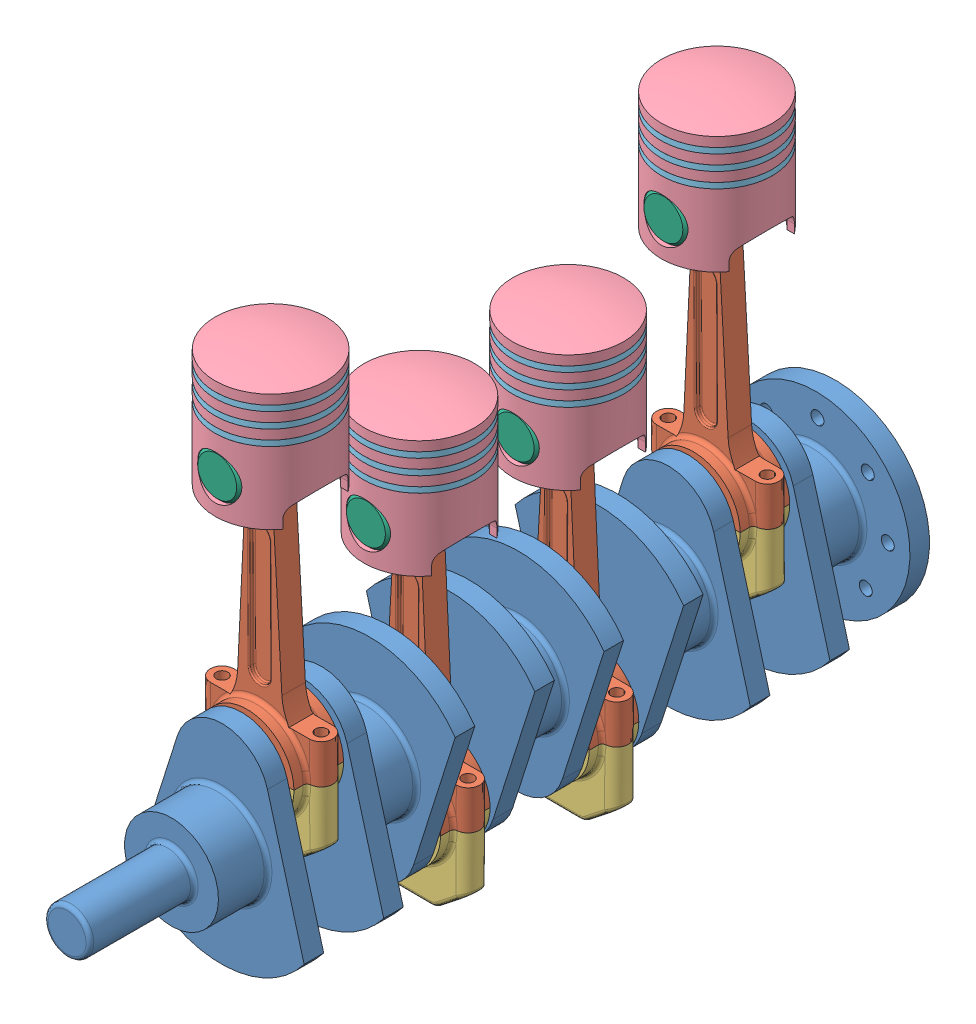
SolidWorks assembly Engine-2003092, configuration Default. Lengths in mm.
Overall size (147.06 418.41 589).
29 component instances, 6 part files, 66 mates.
Components (placement in the parent):
- Crankshaft-1: Crankshaft [Default] at (0 0 456) x (-0.999814 0.019293 0) z (0 0 1) size (144 160 589)
- Connecting rod-1: Connecting rod [Default] at (0 245.19 433) x (0.999991 0.004219 0) z (0 0 1) size (94 223.7 38)
- Connecting rod cap-1: Connecting rod cap [Default] at (0.8489 43.9918 433) x (-0.999991 -0.004219 0) z (0 0 1) size (94 60 38)
- Piston-1: Piston [Default] at (0 219.2199 433) size (85 95 85)
- Piston ring-1: Piston ring [Default] at (0 297.6199 433) size (85 4.3 85)
- Piston Pin-1: Piston Pin [Default] at (0 245.19 433) size (33.8 33.8 82)
- Piston ring-2: Piston ring [Default] at (0 286.0199 433) x (0.546944 0 -0.837169) z (0.837169 0 0.546944) size (85 4.3 85)
- Piston ring-4: Piston ring [Default] at (0 274.4199 433) x (0.546944 0 -0.837169) z (0.837169 0 0.546944) size (85 4.3 85)
- Piston-2: Piston [Default] at (0 131.2362 319) size (85 95 85)
- Piston ring-6: Piston ring [Default] at (0 209.6362 319) x (0.941458 0 -0.337131) z (0.337131 0 0.941458) size (85 4.3 85)
- Piston ring-7: Piston ring [Default] at (0 198.0362 319) x (0.23269 0 -0.972551) z (0.972551 0 0.23269) size (85 4.3 85)
- Piston ring-8: Piston ring [Default] at (0 186.4362 319) x (0.23269 0 -0.972551) z (0.972551 0 0.23269) size (85 4.3 85)
- Piston Pin-2: Piston Pin [Default] at (0 157.2064 319) x (0.216826 -0.97621 0) z (0 0 1) size (33.8 33.8 82)
- Connecting rod-2: Connecting rod [Default] at (0 157.2064 319) x (0.999991 -0.004219 0) z (0 0 1) size (94 223.7 38)
- Connecting rod cap-2: Connecting rod cap [Default] at (-0.8489 -43.9918 319) x (-0.999991 0.004219 0) z (0 0 1) size (94 60 38)
- Piston-4: Piston [Default] at (0 131.2362 205) x (-1 0 0) z (0 0 -1) size (85 95 85)
- Piston ring-12: Piston ring [Default] at (0 209.6362 205) x (0.790546 0 -0.612403) z (0.612403 0 0.790546) size (85 4.3 85)
- Piston ring-13: Piston ring [Default] at (0 198.0362 205) x (-0.0803 0 -0.996771) z (0.996771 0 -0.0803) size (85 4.3 85)
- Piston ring-14: Piston ring [Default] at (0 186.4362 205) x (-0.0803 0 -0.996771) z (0.996771 0 -0.0803) size (85 4.3 85)
- Piston Pin-4: Piston Pin [Default] at (0 157.2064 205) x (-0.34202 0.939693 0) z (0 0 -1) size (33.8 33.8 82)
- Connecting rod-4: Connecting rod [Default] at (0 157.2064 205) x (-0.999991 0.004219 0) z (0 0 -1) size (94 223.7 38)
- Connecting rod cap-4: Connecting rod cap [Default] at (-0.8489 -43.9918 205) x (0.999991 -0.004219 0) z (0 0 -1) size (94 60 38)
- Piston-6: Piston [Default] at (0 219.2199 91) x (-1 0 0) z (0 0 -1) size (85 95 85)
- Piston ring-18: Piston ring [Default] at (0 297.6199 91) x (0.6 0 -0.8) z (0.8 0 0.6) size (85 4.3 85)
- Piston ring-19: Piston ring [Default] at (0 286.0199 91) x (-0.341569 0 -0.939857) z (0.939857 0 -0.341569) size (85 4.3 85)
- Piston ring-20: Piston ring [Default] at (0 274.4199 91) x (-0.341569 0 -0.939857) z (0.939857 0 -0.341569) size (85 4.3 85)
- Piston Pin-6: Piston Pin [Default] at (0 245.19 91) x (-0.5 0.866025 0) z (0 0 -1) size (33.8 33.8 82)
- Connecting rod-6: Connecting rod [Default] at (0 245.19 91) x (-0.999991 -0.004219 0) z (0 0 -1) size (94 223.7 38)
- Connecting rod cap-6: Connecting rod cap [Default] at (0.8489 43.9918 91) x (0.999991 0.004219 0) z (0 0 -1) size (94 60 38)
Mates (geometry in assembly coordinates):
- Concentric1: concentric anti-aligned: cylinder of Crankshaft-1 through (0 0 589) axis (0 0 -1) radius 17.5
- Coincident1: coincident: plane of Crankshaft-1 through (0 0 589) normal (0 0 1)
- Coincident2: coincident aligned: plane of Piston-1 through (0 219.2199 433) normal (0 0 1); plane of Piston Pin-1 through (0 245.19 433) normal (0 0 1)
- Concentric2: concentric anti-aligned: cylinder of Piston-1 through (0 245.19 390.5) axis (0 0 1) radius 16.9; cylinder of Piston Pin-1 through (0 245.19 474) axis (0 0 -1) radius 16.9
- Concentric3: concentric aligned: cylinder of Piston-1 through (0 309.2199 433) axis (0 -1 0) radius 42.5; cylinder of Piston ring-1 through (0 301.9199 433) axis (0 -1 0) radius 42.5
- Coincident3: coincident anti-aligned: plane of Piston-1 through (0 297.6199 433) normal (0 1 0); plane of Piston ring-1 through (0 297.6199 433) normal (0 -1 0)
- Concentric4: concentric anti-aligned: cylinder of Piston-1 through (0 286.0199 433) axis (0 1 0) radius 39.5; cylinder of Piston ring-2 through (0 290.3199 433) axis (0 -1 0) radius 42.5
- Coincident4: coincident anti-aligned: plane of Piston-1 through (0 286.0199 433) normal (0 1 0); plane of Piston ring-2 through (0 286.0199 433) normal (0 -1 0)
- Concentric5: concentric anti-aligned: cylinder of Piston-1 through (0 274.4199 433) axis (0 1 0) radius 39.5; cylinder of Piston ring-4 through (0 278.7199 433) axis (0 -1 0) radius 42.5
- Coincident5: coincident anti-aligned: plane of Piston-1 through (0 274.4199 433) normal (0 1 0); plane of Piston ring-4 through (0 274.4199 433) normal (0 -1 0)
- Coincident6: coincident aligned: plane of Connecting rod-1 through (0 245.19 433) normal (0 0 1); plane of Piston-1 through (0 219.2199 433) normal (0 0 1)
- Concentric6: concentric aligned: cylinder of Connecting rod-1 through (0 245.19 452) axis (0 0 -1) radius 16.9; cylinder of Piston Pin-1 through (0 245.19 474) axis (0 0 -1) radius 16.9
- Concentric7: concentric aligned: cylinder of Connecting rod-1 through (38.8486 44.1521 433) axis (-0.004219 0.999991 0) radius 4.5; cylinder of Connecting rod cap-1 through (39.1017 -15.8473 433) axis (-0.004219 0.999991 0) radius 4.5
- Concentric8: concentric aligned: cylinder of Connecting rod-1 through (-37.1508 43.8315 433) axis (-0.004219 0.999991 0) radius 4.5; cylinder of Connecting rod cap-1 through (-36.8976 -16.168 433) axis (-0.004219 0.999991 0) radius 4.5
- Coincident7: coincident anti-aligned: plane of Connecting rod-1 through (0.8489 43.9918 452) normal (0.004219 -0.999991 0); plane of Connecting rod cap-1 through (36.8486 44.1437 452) normal (-0.004219 0.999991 0)
- Width1: width anti-aligned: plane of Crankshaft-1 through (0 0 410) normal (0 0 1); plane of Connecting rod-1 through (0 0 456) normal (0 0 -1); plane of Crankshaft-1 through (0 245.19 424) normal (0 0 -1); plane of Connecting rod-1 through (0 245.19 442) normal (0 0 1)
- Concentric9: concentric anti-aligned: cylinder of Crankshaft-1 through (0.8489 43.9918 410) axis (0 0 1) radius 27; cylinder of Connecting rod-1 through (0.8489 43.9918 452) axis (0 0 -1) radius 27
- Concentric10: concentric anti-aligned: cylinder of Piston-1 through (0 309.2199 433) axis (0 -1 0) radius 42.5
- Coincident9: coincident aligned: plane of Piston-2 through (0 131.2362 319) normal (0 0 1); plane of Piston Pin-2 through (0 157.2064 319) normal (0 0 1)
- Concentric11: concentric anti-aligned: cylinder of Piston-2 through (0 157.2064 276.5) axis (0 0 1) radius 16.9; cylinder of Piston Pin-2 through (0 157.2064 360) axis (0 0 -1) radius 16.9
- Concentric12: concentric aligned: cylinder of Piston-2 through (0 221.2362 319) axis (0 -1 0) radius 42.5; cylinder of Piston ring-6 through (0 213.9362 319) axis (0 -1 0) radius 42.5
- Coincident10: coincident anti-aligned: plane of Piston-2 through (0 209.6362 319) normal (0 1 0); plane of Piston ring-6 through (0 209.6362 319) normal (0 -1 0)
- Concentric13: concentric anti-aligned: cylinder of Piston-2 through (0 198.0362 319) axis (0 1 0) radius 39.5; cylinder of Piston ring-7 through (0 202.3362 319) axis (0 -1 0) radius 42.5
- Coincident11: coincident anti-aligned: plane of Piston-2 through (0 198.0362 319) normal (0 1 0); plane of Piston ring-7 through (0 198.0362 319) normal (0 -1 0)
- Concentric14: concentric anti-aligned: cylinder of Piston-2 through (0 186.4362 319) axis (0 1 0) radius 39.5; cylinder of Piston ring-8 through (0 190.7362 319) axis (0 -1 0) radius 42.5
- Coincident12: coincident anti-aligned: plane of Piston-2 through (0 186.4362 319) normal (0 1 0); plane of Piston ring-8 through (0 186.4362 319) normal (0 -1 0)
- Coincident13: coincident aligned: plane of Piston-2 through (0 131.2362 319) normal (0 0 1); plane of Connecting rod-2 through (0 157.2064 319) normal (0 0 1)
- Concentric15: concentric aligned: cylinder of Piston Pin-2 through (0 157.2064 360) axis (0 0 -1) radius 16.9; cylinder of Connecting rod-2 through (0 157.2064 338) axis (0 0 -1) radius 16.9
- Concentric16: concentric aligned: cylinder of Connecting rod-2 through (37.1508 -44.1521 319) axis (0.004219 0.999991 0) radius 4.5; cylinder of Connecting rod cap-2 through (36.8976 -104.1516 319) axis (0.004219 0.999991 0) radius 4.5
- Concentric17: concentric aligned: cylinder of Connecting rod-2 through (-38.8486 -43.8315 319) axis (0.004219 0.999991 0) radius 4.5; cylinder of Connecting rod cap-2 through (-39.1017 -103.8309 319) axis (0.004219 0.999991 0) radius 4.5
- Coincident14: coincident anti-aligned: plane of Connecting rod-2 through (-0.8489 -43.9918 338) normal (-0.004219 -0.999991 0); plane of Connecting rod cap-2 through (35.1508 -44.1437 338) normal (0.004219 0.999991 0)
- Width2: width anti-aligned: plane of Crankshaft-1 through (0 0 342) normal (0 0 -1); plane of Connecting rod-2 through (0 0 296) normal (0 0 1); plane of Crankshaft-1 through (0 157.2064 310) normal (0 0 -1); plane of Connecting rod-2 through (0 157.2064 328) normal (0 0 1)
- Concentric18: concentric anti-aligned: cylinder of Crankshaft-1 through (-0.8489 -43.9918 296) axis (0 0 1) radius 27; cylinder of Connecting rod-2 through (-0.8489 -43.9918 338) axis (0 0 -1) radius 27
- Concentric19: concentric anti-aligned: cylinder of Piston-2 through (0 221.2362 319) axis (0 -1 0) radius 42.5
- Coincident21: coincident aligned: plane of Piston-4 through (0 131.2362 205) normal (0 0 -1); plane of Piston Pin-4 through (0 157.2064 205) normal (0 0 -1)
- Concentric27: concentric anti-aligned: cylinder of Piston-4 through (0 157.2064 247.5) axis (0 0 -1) radius 16.9; cylinder of Piston Pin-4 through (0 157.2064 164) axis (0 0 1) radius 16.9
- Concentric28: concentric aligned: cylinder of Piston-4 through (0 221.2362 205) axis (0 -1 0) radius 42.5; cylinder of Piston ring-12 through (0 213.9362 205) axis (0 -1 0) radius 42.5
- Coincident22: coincident anti-aligned: plane of Piston-4 through (0 209.6362 205) normal (0 1 0); plane of Piston ring-12 through (0 209.6362 205) normal (0 -1 0)
- Concentric29: concentric anti-aligned: cylinder of Piston-4 through (0 198.0362 205) axis (0 1 0) radius 39.5; cylinder of Piston ring-13 through (0 202.3362 205) axis (0 -1 0) radius 42.5
- Coincident23: coincident anti-aligned: plane of Piston-4 through (0 198.0362 205) normal (0 1 0); plane of Piston ring-13 through (0 198.0362 205) normal (0 -1 0)
- Concentric30: concentric anti-aligned: cylinder of Piston-4 through (0 186.4362 205) axis (0 1 0) radius 39.5; cylinder of Piston ring-14 through (0 190.7362 205) axis (0 -1 0) radius 42.5
- Coincident24: coincident anti-aligned: plane of Piston-4 through (0 186.4362 205) normal (0 1 0); plane of Piston ring-14 through (0 186.4362 205) normal (0 -1 0)
- Coincident25: coincident aligned: plane of Piston-4 through (0 131.2362 205) normal (0 0 -1); plane of Connecting rod-4 through (0 157.2064 205) normal (0 0 -1)
- Concentric31: concentric aligned: cylinder of Piston Pin-4 through (0 157.2064 164) axis (0 0 1) radius 16.9; cylinder of Connecting rod-4 through (0 157.2064 186) axis (0 0 1) radius 16.9
- Concentric32: concentric aligned: cylinder of Connecting rod-4 through (-38.8486 -43.8315 205) axis (0.004219 0.999991 0) radius 4.5; cylinder of Connecting rod cap-4 through (-39.1017 -103.8309 205) axis (0.004219 0.999991 0) radius 4.5
- Concentric33: concentric aligned: cylinder of Connecting rod-4 through (37.1508 -44.1521 205) axis (0.004219 0.999991 0) radius 4.5; cylinder of Connecting rod cap-4 through (36.8976 -104.1516 205) axis (0.004219 0.999991 0) radius 4.5
- Coincident26: coincident anti-aligned: plane of Connecting rod-4 through (-0.8489 -43.9918 186) normal (-0.004219 -0.999991 0); plane of Connecting rod cap-4 through (-36.8486 -43.8399 186) normal (0.004219 0.999991 0)
- Width3: width anti-aligned: plane of Crankshaft-1 through (0 0 228) normal (0 0 -1); plane of Connecting rod-4 through (0 0 182) normal (0 0 1); plane of Crankshaft-1 through (0 157.2064 214) normal (0 0 1); plane of Connecting rod-4 through (0 157.2064 196) normal (0 0 -1)
- Concentric34: concentric anti-aligned: cylinder of Crankshaft-1 through (-0.8489 -43.9918 228) axis (0 0 -1) radius 27; cylinder of Connecting rod-4 through (-0.8489 -43.9918 186) axis (0 0 1) radius 27
- Concentric35: concentric anti-aligned: cylinder of Piston-4 through (0 221.2362 205) axis (0 -1 0) radius 42.5
- Coincident33: coincident aligned: plane of Piston-6 through (0 219.2199 91) normal (0 0 -1); plane of Piston Pin-6 through (0 245.19 91) normal (0 0 -1)
- Concentric43: concentric anti-aligned: cylinder of Piston-6 through (0 245.19 133.5) axis (0 0 -1) radius 16.9; cylinder of Piston Pin-6 through (0 245.19 50) axis (0 0 1) radius 16.9
- Concentric44: concentric aligned: cylinder of Piston-6 through (0 309.2199 91) axis (0 -1 0) radius 42.5; cylinder of Piston ring-18 through (0 301.9199 91) axis (0 -1 0) radius 42.5
- Coincident34: coincident anti-aligned: plane of Piston-6 through (0 297.6199 91) normal (0 1 0); plane of Piston ring-18 through (0 297.6199 91) normal (0 -1 0)
- Concentric45: concentric anti-aligned: cylinder of Piston-6 through (0 286.0199 91) axis (0 1 0) radius 39.5; cylinder of Piston ring-19 through (0 290.3199 91) axis (0 -1 0) radius 42.5
- Coincident35: coincident anti-aligned: plane of Piston-6 through (0 286.0199 91) normal (0 1 0); plane of Piston ring-19 through (0 286.0199 91) normal (0 -1 0)
- Concentric46: concentric anti-aligned: cylinder of Piston-6 through (0 274.4199 91) axis (0 1 0) radius 39.5; cylinder of Piston ring-20 through (0 278.7199 91) axis (0 -1 0) radius 42.5
- Coincident36: coincident anti-aligned: plane of Piston-6 through (0 274.4199 91) normal (0 1 0); plane of Piston ring-20 through (0 274.4199 91) normal (0 -1 0)
- Coincident37: coincident aligned: plane of Piston-6 through (0 219.2199 91) normal (0 0 -1); plane of Connecting rod-6 through (0 245.19 91) normal (0 0 -1)
- Concentric47: concentric aligned: cylinder of Piston Pin-6 through (0 245.19 50) axis (0 0 1) radius 16.9; cylinder of Connecting rod-6 through (0 245.19 72) axis (0 0 1) radius 16.9
- Concentric48: concentric aligned: cylinder of Connecting rod-6 through (-37.1508 43.8315 91) axis (-0.004219 0.999991 0) radius 4.5; cylinder of Connecting rod cap-6 through (-36.8976 -16.168 91) axis (-0.004219 0.999991 0) radius 4.5
- Concentric49: concentric aligned: cylinder of Connecting rod-6 through (38.8486 44.1521 91) axis (-0.004219 0.999991 0) radius 4.5; cylinder of Connecting rod cap-6 through (39.1017 -15.8473 91) axis (-0.004219 0.999991 0) radius 4.5
- Coincident38: coincident anti-aligned: plane of Connecting rod-6 through (0.8489 43.9918 72) normal (0.004219 -0.999991 0); plane of Connecting rod cap-6 through (-35.1508 43.8399 72) normal (-0.004219 0.999991 0)
- Width4: width anti-aligned: plane of Crankshaft-1 through (0 0 114) normal (0 0 -1); plane of Connecting rod-6 through (0 0 68) normal (0 0 1); plane of Crankshaft-1 through (0 245.19 100) normal (0 0 1); plane of Connecting rod-6 through (0 245.19 82) normal (0 0 -1)
- Concentric50: concentric anti-aligned: cylinder of Crankshaft-1 through (0.8489 43.9918 114) axis (0 0 -1) radius 27; cylinder of Connecting rod-6 through (0.8489 43.9918 72) axis (0 0 1) radius 27
- Concentric51: concentric anti-aligned: cylinder of Piston-6 through (0 309.2199 91) axis (0 -1 0) radius 42.5
